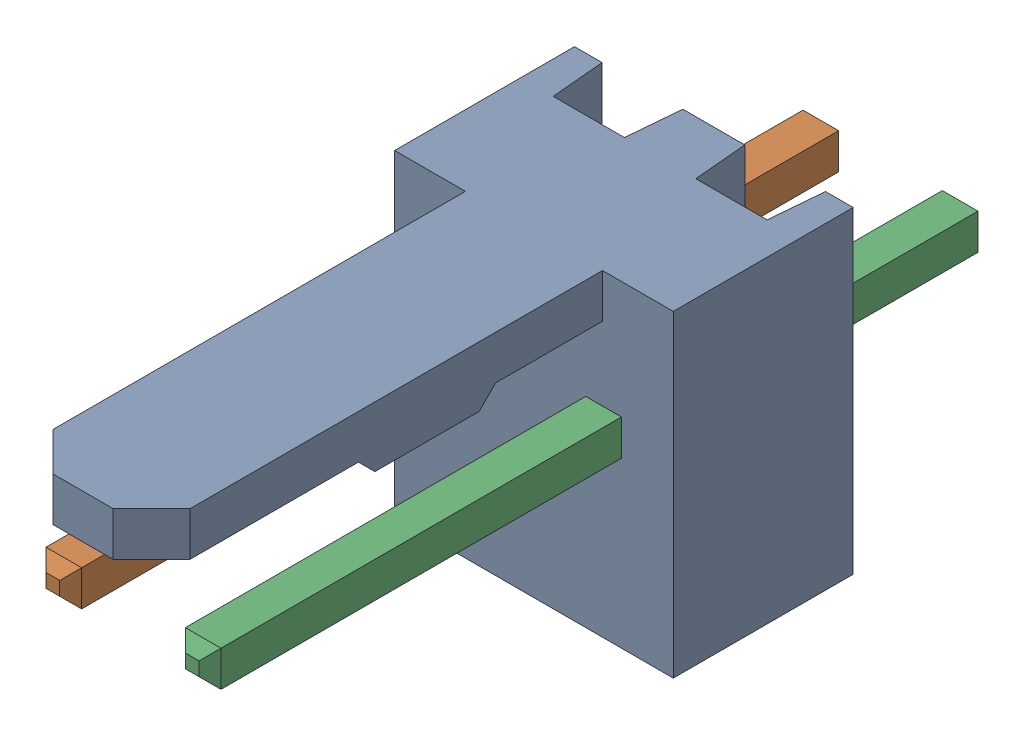
SolidWorks assembly Molex PCB 2 pin v2_6, configuration Predeterminado. Lengths in mm.
Overall size (5.08 5.79 14.92).
3 component instances, 2 part files, 0 mates.
Components (placement in the parent):
- BASE9710016_1-1: BASE9710016_1 [Predeterminado] at (2.54 2.895 -8.22) size (5.08 5.79 11.5)
- PINO9710016_1-1: PINO9710016_1 [Predeterminado] at (1.27 3.325 -0.72) size (0.65 0.65 14.2)
- PINO9710016_1-2: PINO9710016_1 [Predeterminado] at (3.81 3.325 -0.72) size (0.65 0.65 14.2)
